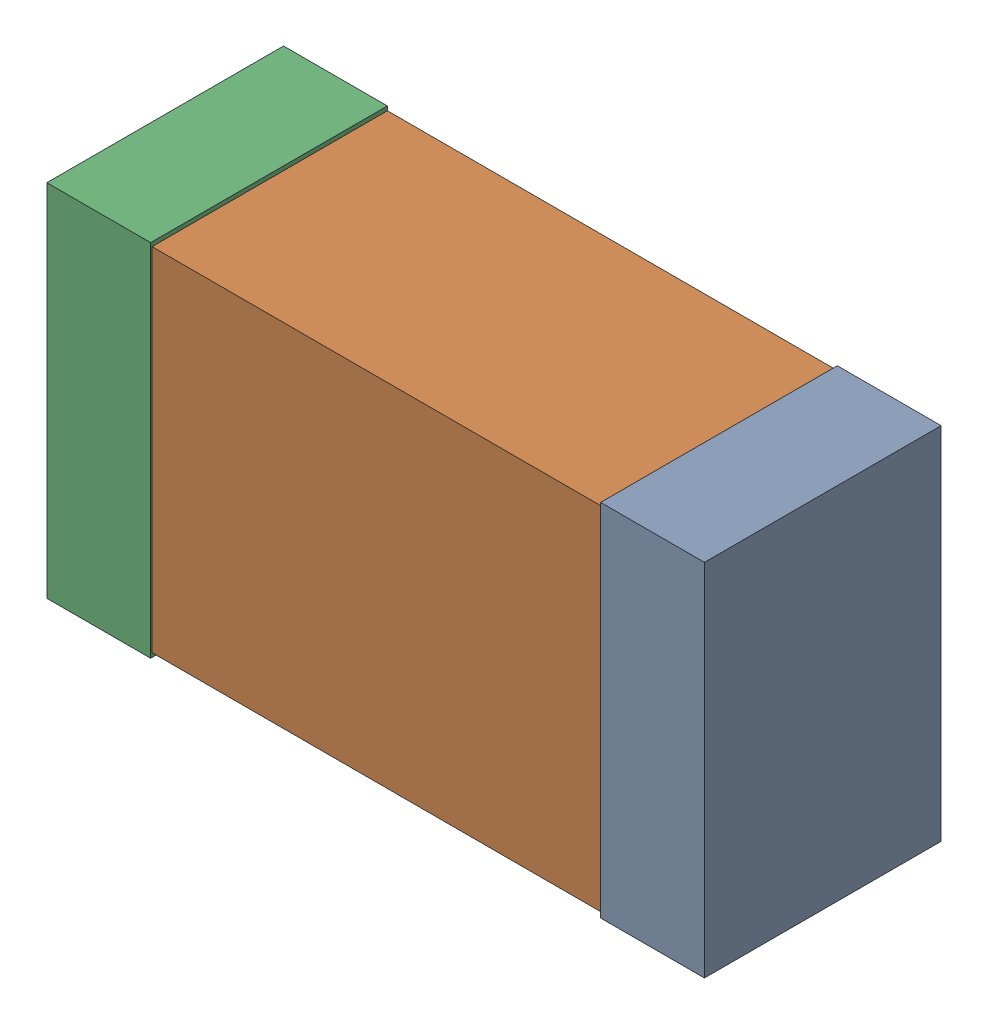
SolidWorks assembly C8Kanaloa_v2.0.0_GPIO_b, configuration Default. Lengths in mm.
Overall size (2.38 1.3 0.85).
6 component instances, 2 part files, 0 mates.
Components (placement in the parent):
- 352877648-1: 352877648 [Default] at (144.256 102.997 0) size (0.38 1.3 0.85)
  - Extruded_14-1: Extruded_14 [Default] at origin size (0.38 1.3 0.85)
- 352877904-1: 352877904 [Default] at (143.256 102.997 0) size (2.2 1.27 0.85)
  - Extruded_18-1: Extruded_18 [Default] at origin size (2.2 1.27 0.85)
- 352877648-2: 352877648 [Default] at (142.256 102.997 0) size (0.38 1.3 0.85)
  - Extruded_14-1: Extruded_14 [Default] at origin size (0.38 1.3 0.85)
